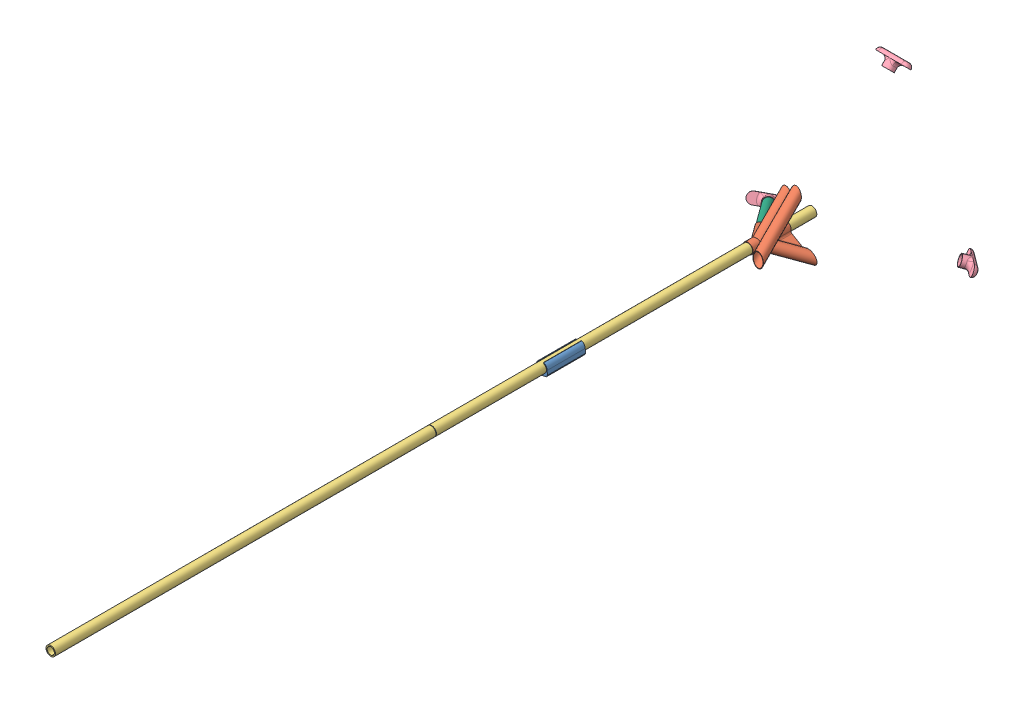
SolidWorks assembly Assemblage1, configuration Défaut. Lengths in mm.
Overall size (555.27 462.76 2173.15).
9 component instances, 6 part files, 10 mates.
Components (placement in the parent):
- accroche-1: accroche [Défaut] at (22.1176 -100.2394 678.1582) x (0.981258 0.192697 0) z (0 0 1) size (28.8 29.65 100)
- tri_equerre-1: tri_equerre [Défaut] at (22.1176 -100.2394 136.2263) size (163.45 158.31 100)
- tube_acrilique-3: tube_acrilique [Défaut] at (22.1176 -100.2394 67.6102) size (25 25 1000)
- tube_acrilique-4: tube_acrilique [Défaut] at (22.1176 -100.2394 1068.6102) size (25 25 1000)
- pied_rond_decale-1: pied_rond_decale [Défaut] at (-167.8636 -209.9251 -9.7016) x (0.78033 -0.126826 -0.612372) z (0.612372 0.353553 0.707107) size (87.1 27.1 30)
- pied_rond_decale-2: pied_rond_decale [Défaut] at (303.7528 -143.5113 -66.0068) x (0.78033 0.126826 0.612372) z (-0.612372 0.353553 0.707107) size (87.1 27.1 30)
- pied_rond_decale-3: pied_rond_decale [Défaut] at (98.8935 214.5677 -69.259) x (1 0 0) z (0 -0.707107 0.707107) size (87.1 27.1 30)
- jonction_tube_int-1: jonction_tube_int [Défaut] at (22.1176 -100.2394 1068.1102) x (0 0 -1) z (1 0 0) size (100.61 20.06 25.5)
- tube_acrilique_30-6: tube_acrilique_30 [Défaut] at (-167.8636 -209.9251 -9.7016) x (0.78033 -0.126826 -0.612372) z (0.612372 0.353553 0.707107) size (25 25 300)
Mates (geometry in assembly coordinates):
- Coaxiale3: concentric aligned: cylinder of tri_equerre-1 through (22.1176 -100.2394 236.2263) axis (0 0 -1) radius 12.7; cylinder of tube_acrilique-3 through (22.1176 -100.2394 1067.6102) axis (0 0 -1) radius 12.5
- Coaxiale4: concentric aligned: cylinder of accroche-1 through (22.1176 -100.2394 778.1582) axis (0 0 -1) radius 12.4; cylinder of tube_acrilique-3 through (22.1176 -100.2394 1067.6102) axis (0 0 -1) radius 12.5
- Coaxiale5: concentric aligned: cylinder of accroche-1 through (22.1176 -100.2394 778.1582) axis (0 0 -1) radius 12.4; cylinder of tube_acrilique-4 through (22.1176 -100.2394 2068.6102) axis (0 0 -1) radius 12.5
- Coaxiale11: concentric anti-aligned: cylinder of tube_acrilique-3 through (22.1176 -100.2394 1067.6102) axis (0 0 -1) radius 9.5; cylinder of jonction_tube_int-1 through (22.1176 -100.2394 1018.1102) axis (0 0 1) radius 9.75
- Coaxiale12: concentric anti-aligned: cylinder of tube_acrilique-4 through (22.1176 -100.2394 2068.6102) axis (0 0 -1) radius 9.5; cylinder of jonction_tube_int-1 through (22.1176 -100.2394 1018.1102) axis (0 0 1) radius 9.75
- Coïncidente6: coincident anti-aligned: plane of tube_acrilique-3 through (22.1176 -100.2394 1067.6102) normal (0 0 1); plane of jonction_tube_int-1 through (22.1176 -100.2394 1067.6102) normal (0 0 -1)
- Coïncidente7: coincident anti-aligned: plane of tube_acrilique-4 through (22.1176 -100.2394 1068.6102) normal (0 0 -1); plane of jonction_tube_int-1 through (22.1176 -100.2394 1068.6102) normal (0 0 1)
- Coïncidente8: coincident: plane of pied_rond-1 through (-371.1106 -225.6959 -226.9118) normal (0.612372 0.353553 0.707107); plane of tube_acrilique_30-6 through (-371.1106 -225.6959 -226.9118) normal (-0.612372 -0.353553 -0.707107)
- Coaxiale13: concentric aligned: cylinder of pied_rond-1 through (-155.6161 -202.854 4.4405) axis (-0.612372 -0.353553 -0.707107) radius 12.55; cylinder of tube_acrilique_30-6 through (15.8482 -103.8591 202.4304) axis (-0.612372 -0.353553 -0.707107) radius 9.5
- Coaxiale15: concentric anti-aligned: cylinder of tri_equerre-1 through (-70.1298 -153.4985 103.1516) axis (0.612372 0.353553 0.707107) radius 12.7; cylinder of tube_acrilique_30-6 through (15.8482 -103.8591 202.4304) axis (-0.612372 -0.353553 -0.707107) radius 9.5
